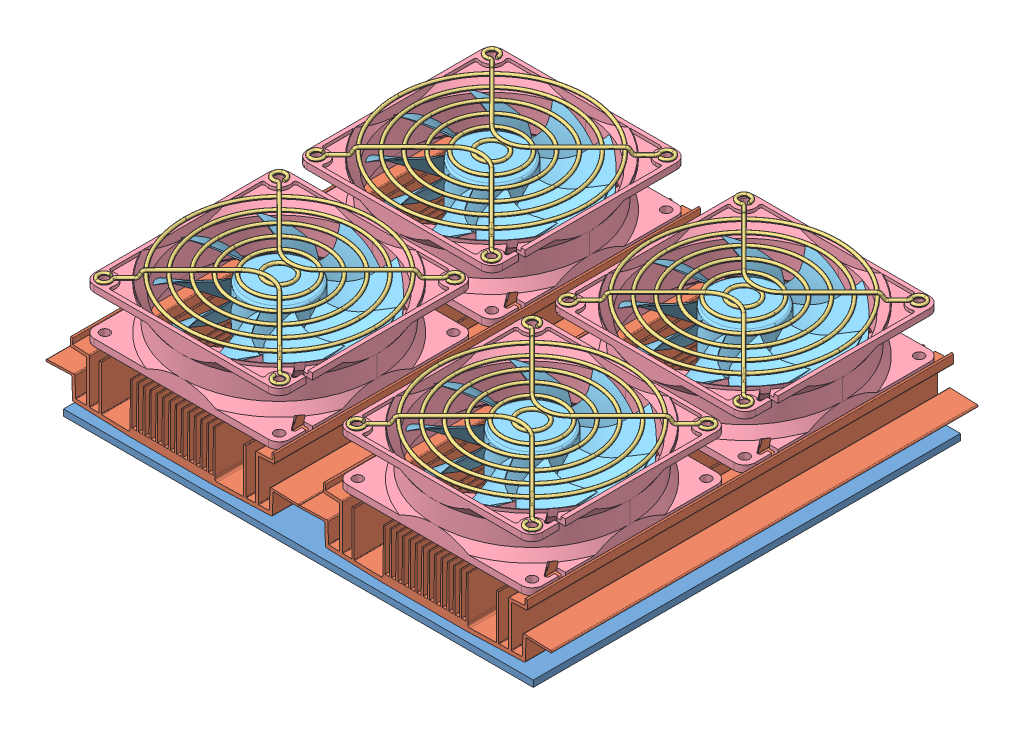
SolidWorks assembly Peltier assembly, configuration Default. Lengths in mm.
Overall size (238 60.94 201).
23 component instances, 5 part files, 30 mates.
Components (placement in the parent):
- Cold plate-1: Cold plate [Default] at (91.398 99.6959 175.559) size (221 3 201)
- Heatsink-1: Heatsink [Default] at (31.898 106.6959 75.309) size (119 27.24 200.5)
- Heatsink-2: Heatsink [Default] at (150.898 106.6959 75.309) size (119 27.24 200.5)
- 92mm Fan Guard-1: 92mm Fan Guard [Default] at (32.0916 156.652 125.8154) x (0.999999 0 0.001368) z (-0.001368 0 0.999999) size (90.49 4.78 90.49)
- F9-1: F9 [Default] at (64.0963 125.1552 120.7546) size (93.27 26.59 93.52)
  - F9.STEP-1: F9.STEP [Default] at origin size (93.27 26.59 93.52)
    - F9 body.STEP-1: F9 body.STEP [Default] at (-78.1983 5.7094 50.7544) size (92.01 26.59 92.01)
    - F9 fan.STEP-1: F9 fan.STEP [Default] at (-74.2115 10.4094 -44.9134) x (-0.083202 0 0.996533) z (-0.996533 0 -0.083202) size (86.63 20 86.36)
- F9-2: F9 [Default] at (64.0963 125.1552 220.8546) size (93.27 26.59 93.52)
  - F9.STEP-1: F9.STEP [Default] at origin size (93.27 26.59 93.52)
    - F9 body.STEP-1: F9 body.STEP [Default] at (-78.1983 5.7094 50.7544) size (92.01 26.59 92.01)
    - F9 fan.STEP-1: F9 fan.STEP [Default] at (-74.2115 10.4094 -44.9134) x (-0.083202 0 0.996533) z (-0.996533 0 -0.083202) size (86.63 20 86.36)
- F9-3: F9 [Default] at (183.0963 125.1552 120.7546) size (93.27 26.59 93.52)
  - F9.STEP-1: F9.STEP [Default] at origin size (93.27 26.59 93.52)
    - F9 body.STEP-1: F9 body.STEP [Default] at (-78.1983 5.7094 50.7544) size (92.01 26.59 92.01)
    - F9 fan.STEP-1: F9 fan.STEP [Default] at (-74.2115 10.4094 -44.9134) x (-0.083202 0 0.996533) z (-0.996533 0 -0.083202) size (86.63 20 86.36)
- F9-4: F9 [Default] at (183.0963 125.1552 220.8546) size (93.27 26.59 93.52)
  - F9.STEP-1: F9.STEP [Default] at origin size (93.27 26.59 93.52)
    - F9 body.STEP-1: F9 body.STEP [Default] at (-78.1983 5.7094 50.7544) size (92.01 26.59 92.01)
    - F9 fan.STEP-1: F9 fan.STEP [Default] at (-74.2115 10.4094 -44.9134) x (-0.083202 0 0.996533) z (-0.996533 0 -0.083202) size (86.63 20 86.36)
- 92mm Fan Guard-3: 92mm Fan Guard [Default] at (151.148 156.652 225.859) size (90.49 4.78 90.49)
- 92mm Fan Guard-4: 92mm Fan Guard [Default] at (150.6091 156.652 125.7201) x (1 0 0.000944) z (-0.000944 0 1) size (90.49 4.78 90.49)
- 92mm Fan Guard-5: 92mm Fan Guard [Default] at (32.2135 156.652 225.7935) x (0.999999 0 -0.001588) z (0.001588 0 0.999999) size (90.49 4.78 90.49)
Mates (geometry in assembly coordinates):
- Distance1: distance = 4 mm anti-aligned: plane of Heatsink-1 through (11.898 106.6959 275.809) normal (0 -1 0); plane of Cold plate-1 through (91.398 102.6959 175.559) normal (0 1 0)
- Width1: width anti-aligned: plane of Heatsink-1 through (-27.102 118.1835 275.809) normal (0 0 1); plane of Cold plate-1 through (-27.102 118.1835 75.309) normal (0 0 -1); plane of Heatsink-1 through (-19.102 102.6959 75.059) normal (0 0 -1); plane of Cold plate-1 through (-19.102 102.6959 276.059) normal (0 0 1)
- Coincident3: coincident aligned: plane of Heatsink-1 through (11.898 106.6959 275.809) normal (0 -1 0); plane of Heatsink-2 through (130.898 106.6959 275.809) normal (0 -1 0)
- Coincident4: coincident aligned: plane of Heatsink-1 through (-27.102 118.1835 275.809) normal (0 0 1); plane of Heatsink-2 through (91.898 118.1835 275.809) normal (0 0 1)
- Tangent1: tangent anti-aligned: cylinder of Heatsink-1 through (90.898 118.1835 275.809) axis (0 0 -1) radius 0.5; cylinder of Heatsink-2 through (91.898 118.1835 275.809) axis (0 0 -1) radius 0.5
- Width2: width aligned: plane of Heatsink-1 through (-15.4649 118.0896 275.809) normal (-0.999391 -0.034899 0); plane of Cold plate-1 through (198.261 118.0896 275.809) normal (0.999391 -0.034899 0); plane of Heatsink-2 through (201.898 102.6959 276.059) normal (1 0 0); plane of Cold plate-1 through (-19.102 102.6959 276.059) normal (-1 0 0)
- Concentric2: concentric aligned: circle of 92mm Fan Guard-1; cylinder of F9-1/F9.STEP-1/F9 body.STEP-1 through (-9.102 155.8646 84.509) axis (0 -1 0) radius 2.25
- Tangent3: tangent anti-aligned: cylinder of 92mm Fan Guard-1 through (66.0854 156.652 159.9023) axis (0.706139 0 0.708073) radius 0.7874; plane of F9-1/F9.STEP-1/F9 body.STEP-1 through (31.898 155.8646 125.509) normal (0 1 0)
- Width3: width anti-aligned: plane of F9-1/F9.STEP-1/F9 body.STEP-1 through (-14.102 155.8646 125.509) normal (-1 0 0); plane of Heatsink-1 through (77.898 155.8646 84.509) normal (1 0 0); plane of F9-1/F9.STEP-1/F9 body.STEP-1 through (78.7536 133.4111 275.809) normal (-0.99863 -0.052336 0); plane of Heatsink-1 through (-14.9575 133.4111 275.809) normal (0.99863 -0.052336 0)
- Coincident5: coincident aligned: line of Heatsink-1 through (78.8871 130.8646 275.809) axis (0 0 -1); plane of F9-1/F9.STEP-1/F9 body.STEP-1 through (72.898 130.8646 84.509) normal (0 -1 0)
- Distance2: distance = 4.2 mm aligned: plane of F9-1/F9.STEP-1/F9 body.STEP-1 through (31.898 155.8646 79.509) normal (0 0 -1); plane of Heatsink-1 through (-27.102 118.1835 75.309) normal (0 0 -1)
- Coincident6: coincident aligned: plane of F9-1/F9.STEP-1/F9 body.STEP-1 through (72.898 130.8646 84.509) normal (0 -1 0); plane of F9-2/F9.STEP-1/F9 body.STEP-1 through (72.898 130.8646 184.609) normal (0 -1 0)
- Coincident7: coincident aligned: plane of F9-1/F9.STEP-1/F9 body.STEP-1 through (-14.102 155.8646 125.509) normal (-1 0 0); plane of F9-2/F9.STEP-1/F9 body.STEP-1 through (-14.102 155.8646 225.609) normal (-1 0 0)
- Distance3: distance = 4.2 mm aligned: plane of F9-2/F9.STEP-1/F9 body.STEP-1 through (31.898 155.8646 271.609) normal (0 0 1); plane of Heatsink-1 through (-27.102 118.1835 275.809) normal (0 0 1)
- Lock1: lock: unknown of 92mm Fan Guard-1; unknown of F9-1/F9.STEP-1/F9 body.STEP-1
- Concentric9: concentric aligned: cylinder of F9-2/F9.STEP-1/F9 body.STEP-1 through (-9.102 155.8646 184.609) axis (0 -1 0) radius 2.25; circle of 92mm Fan Guard-5
- Tangent11: tangent anti-aligned: plane of F9-2/F9.STEP-1/F9 body.STEP-1 through (31.898 155.8646 225.609) normal (0 1 0); cylinder of 92mm Fan Guard-5 through (-1.8809 156.652 191.8072) axis (-0.708228 0 -0.705983) radius 0.7874
- Lock2: lock: unknown of F9-2/F9.STEP-1/F9 body.STEP-1; unknown of 92mm Fan Guard-5
- Concentric11: concentric aligned: cylinder of F9-4/F9.STEP-1/F9 body.STEP-1 through (109.898 155.8646 184.609) axis (0 -1 0) radius 2.25; circle of 92mm Fan Guard-3
- Tangent13: tangent anti-aligned: plane of F9-4/F9.STEP-1/F9 body.STEP-1 through (150.898 155.8646 225.609) normal (0 1 0); cylinder of 92mm Fan Guard-3 through (117.1077 156.652 191.8186) axis (-0.707107 0 -0.707107) radius 0.7874
- Lock4: lock: unknown of F9-4/F9.STEP-1/F9 body.STEP-1; unknown of 92mm Fan Guard-3
- Coincident9: coincident: line of Heatsink-2 through (197.8871 130.8646 275.809) axis (0 0 -1); plane of F9-3/F9.STEP-1/F9 body.STEP-1 through (191.898 130.8646 84.509) normal (0 -1 0)
- Width4: width anti-aligned: plane of F9-3/F9.STEP-1/F9 body.STEP-1 through (196.898 155.8646 84.509) normal (1 0 0); plane of Heatsink-2 through (104.898 155.8646 125.509) normal (-1 0 0); plane of F9-3/F9.STEP-1/F9 body.STEP-1 through (104.0425 133.4111 275.809) normal (0.99863 -0.052336 0); plane of Heatsink-2 through (197.7536 133.4111 275.809) normal (-0.99863 -0.052336 0)
- Distance5: distance = 4.2 mm aligned: plane of F9-3/F9.STEP-1/F9 body.STEP-1 through (150.898 155.8646 79.509) normal (0 0 -1); plane of Heatsink-2 through (91.898 118.1835 75.309) normal (0 0 -1)
- Coincident10: coincident aligned: plane of F9-3/F9.STEP-1/F9 body.STEP-1 through (191.898 130.8646 84.509) normal (0 -1 0); plane of F9-4/F9.STEP-1/F9 body.STEP-1 through (191.898 130.8646 184.609) normal (0 -1 0)
- Coincident11: coincident aligned: plane of F9-3/F9.STEP-1/F9 body.STEP-1 through (196.898 155.8646 84.509) normal (1 0 0); plane of F9-4/F9.STEP-1/F9 body.STEP-1 through (196.898 155.8646 184.609) normal (1 0 0)
- Distance6: distance = 4.2 mm aligned: plane of F9-4/F9.STEP-1/F9 body.STEP-1 through (150.898 155.8646 271.609) normal (0 0 1); plane of Heatsink-2 through (91.898 118.1835 275.809) normal (0 0 1)
- Concentric12: concentric anti-aligned: cylinder of F9-3/F9.STEP-1/F9 body.STEP-1 through (191.898 155.8646 84.509) axis (0 -1 0) radius 2.25; circle of 92mm Fan Guard-4
- Tangent14: tangent anti-aligned: plane of F9-3/F9.STEP-1/F9 body.STEP-1 through (150.898 155.8646 125.509) normal (0 1 0); cylinder of 92mm Fan Guard-4 through (189.0016 156.652 87.4) axis (-0.707774 0 0.706439) radius 0.7874
- Lock5: lock: unknown of F9-3/F9.STEP-1/F9 body.STEP-1; unknown of 92mm Fan Guard-4
